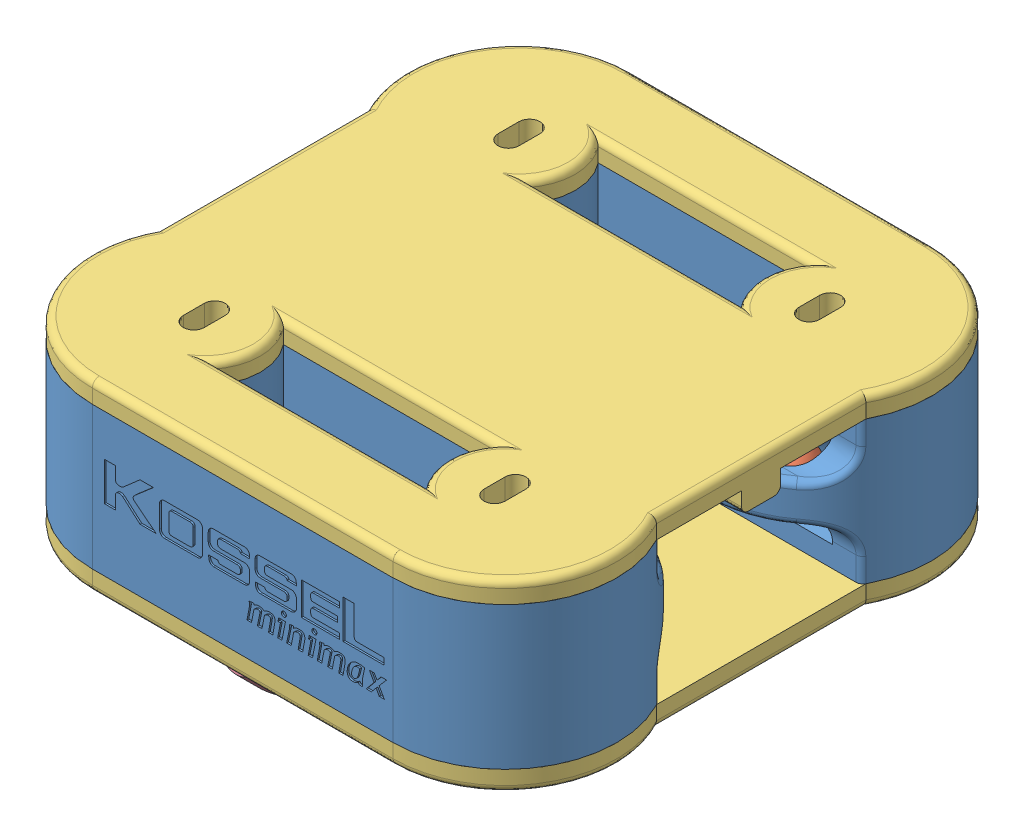
SolidWorks assembly assembled_bearing, configuration Default. Lengths in mm.
Overall size (75 49.18 77).
26 component instances, 5 part files, 17 mates.
Components (placement in the parent):
- loaded_bearing_body-1: loaded_bearing_body [Default] at origin size (75 20.4 32)
  - bearing_body-2: bearing_body [Default] at origin size (75 20.4 32)
  - delrin_ball_5-16_inch-20: delrin_ball_5-16_inch [Default] at (-21.5 0 -10.4333) size (7.94 7.94 7.94)
  - delrin_ball_5-16_inch-21: delrin_ball_5-16_inch [Default] at (-28.7803 0 -7.4723) size (7.94 7.94 7.94)
  - delrin_ball_5-16_inch-22: delrin_ball_5-16_inch [Default] at (-31.9288 0 -0.2689) size (7.94 7.94 7.94)
  - delrin_ball_5-16_inch-23: delrin_ball_5-16_inch [Default] at (-29.1561 0 7.0868) size (7.94 7.94 7.94)
  - delrin_ball_5-16_inch-24: delrin_ball_5-16_inch [Default] at (-22.036 0 10.4195) size (7.94 7.94 7.94)
  - delrin_ball_5-16_inch-25: delrin_ball_5-16_inch [Default] at (-13.9756 0 10.4333) size (7.94 7.94 7.94)
  - delrin_ball_5-16_inch-26: delrin_ball_5-16_inch [Default] at (-5.9163 0 10.4333) size (7.94 7.94 7.94)
  - delrin_ball_5-16_inch-27: delrin_ball_5-16_inch [Default] at (2.143 0 10.4333) size (7.94 7.94 7.94)
  - delrin_ball_5-16_inch-28: delrin_ball_5-16_inch [Default] at (10.2043 0 10.4333) size (7.94 7.94 7.94)
  - delrin_ball_5-16_inch-29: delrin_ball_5-16_inch [Default] at (18.2636 0 10.4333) size (7.94 7.94 7.94)
  - delrin_ball_5-16_inch-30: delrin_ball_5-16_inch [Default] at (26.1539 0 9.3383) size (7.94 7.94 7.94)
  - delrin_ball_5-16_inch-31: delrin_ball_5-16_inch [Default] at (31.3507 0 3.4405) size (7.94 7.94 7.94)
  - delrin_ball_5-16_inch-32: delrin_ball_5-16_inch [Default] at (30.9555 0 -4.4119) size (7.94 7.94 7.94)
  - delrin_ball_5-16_inch-33: delrin_ball_5-16_inch [Default] at (25.193 0 -9.7582) size (7.94 7.94 7.94)
  - delrin_ball_5-16_inch-34: delrin_ball_5-16_inch [Default] at (17.215 0 -10.4333) size (7.94 7.94 7.94)
  - delrin_ball_5-16_inch-35: delrin_ball_5-16_inch [Default] at (9.1557 0 -10.4333) size (7.94 7.94 7.94)
  - delrin_ball_5-16_inch-36: delrin_ball_5-16_inch [Default] at (1.0944 0 -10.4333) size (7.94 7.94 7.94)
  - delrin_ball_5-16_inch-37: delrin_ball_5-16_inch [Default] at (-6.9649 0 -10.4333) size (7.94 7.94 7.94)
  - delrin_ball_5-16_inch-38: delrin_ball_5-16_inch [Default] at (-15.0243 0 -10.4333) size (7.94 7.94 7.94)
- bearing_assembly_plate-1: bearing_assembly_plate [Outside] at (0 10.2 0) x (1 0 0) z (0 1 0) size (75 77 6)
- bearing_body-1: bearing_body [Default] at (0 0 45) x (-1 0 0) z (0 0 -1) size (75 20.4 32)
- bearing_assembly_plate-2: bearing_assembly_plate [Rodside-Nohole] at (0 -10.2 45) x (1 0 0) z (0 -1 0) size (75 77 12.8)
- rod_and_belt_carriage-1: rod_and_belt_carriage [Nohole] at (-19.4203 -23 22.5) x (0 0 1) z (1 0 0) size (40 12.98 32.4)
- Part2^assembled_bearing-1: Part2^assembled_bearing [Default] at (-19.4203 -23 22.5) x (0 0 -1) z (0 1 0) size (33.02 13.44 9.81) (virtual)
Mates (geometry in assembly coordinates):
- InPlace1: in place: plane of loaded_bearing_body-1/bearing_body-2 through (-22 10.2 0) normal (0 1 0); plane of bearing_assembly_plate-1 through (0 10.2 0) normal (0 1 0); moOrthogonalPlaneRef_w of loaded_bearing_body-1/bearing_body-2 through (-22 10.2 0) normal (0 1 0); plane of bearing_assembly_plate-1 through (0 10.2 0) normal (0 0 -1); plane of loaded_bearing_body-1/bearing_body-2 through (-22 10.2 0) normal (0 1 0); line of bearing_assembly_plate-1 through (-55 0 10.2) axis (0 1 0); plane of loaded_bearing_body-1/bearing_body-2 through (-21.5 10.2 0) normal (0 1 0); unknown of bearing_assembly_plate-1
- Coincident1: coincident aligned: plane of loaded_bearing_body-1/bearing_body-2; plane of bearing_assembly_plate-1
- Coincident2: coincident aligned: moOrthogonalPlaneRef_w of loaded_bearing_body-1/bearing_body-2 through (0 10.2 0) normal (0 0 -1); plane of bearing_assembly_plate-1 through (0 10.2 0) normal (0 0 -1)
- Coincident3: coincident anti-aligned: moOrthogonalPlaneRef_w of loaded_bearing_body-1/bearing_body-2 through (0 10.2 0) normal (-1 0 0); plane of bearing_assembly_plate-1
- Coincident4: coincident anti-aligned: plane of bearing_assembly_plate-1 through (-21.5 10.2 0) normal (0 -1 0); plane of bearing_body-1 through (21.5 10.2 45) normal (0 1 0)
- Coincident5: coincident aligned: plane of bearing_assembly_plate-1 through (21.5 13.2 61) normal (0 0 1); plane of bearing_body-1 through (-21.5 -10.2 61) normal (0 0 1)
- Coincident6: coincident anti-aligned: line of bearing_assembly_plate-1 through (21.5 12.2 61) axis (0 -1 0); line of bearing_body-1 through (21.5 -10.2 61) axis (0 1 0)
- Coincident7: coincident anti-aligned: plane of loaded_bearing_body-1/bearing_body-2 through (-21.5 -10.2 0) normal (0 -1 0); plane of bearing_assembly_plate-2 through (-21.5 -10.2 45) normal (0 1 0)
- Coincident8: coincident aligned: plane of loaded_bearing_body-1/bearing_body-2 through (21.5 -10.2 -16) normal (0 0 -1); plane of bearing_assembly_plate-2 through (21.5 -13.2 -16) normal (0 0 -1)
- Coincident9: coincident aligned: line of loaded_bearing_body-1/bearing_body-2 through (-21.5 -10.2 -16) axis (0 1 0); line of bearing_assembly_plate-2 through (-21.5 -12.2 -16) axis (0 1 0)
- Coincident10: coincident anti-aligned: plane of bearing_assembly_plate-2 through (0 -23 45) normal (0 -1 0); plane of rod_and_belt_carriage-1 through (-19.4203 -23 22.5) normal (0 1 0)
- Coincident11: coincident aligned: plane of bearing_assembly_plate-2 through (-35.6203 -13.2 37.4755) normal (-1 0 0); plane of rod_and_belt_carriage-1 through (-35.6203 -27 36) normal (-1 0 0)
- Coincident12: coincident aligned: plane of bearing_assembly_plate-2 through (-3.2203 -23 9) normal (0 0 -1); plane of rod_and_belt_carriage-1 through (-3.2203 -27 9) normal (0 0 -1)
- InPlace2: in place: plane of rod_and_belt_carriage-1 through (-19.4203 -23 22.5) normal (0 1 0); plane of ? through (0 -23 0) normal (0 1 0); plane of rod_and_belt_carriage-1 through (-19.4203 -23 22.5) normal (0 1 0); plane of ? through (0 -23 0) normal (0 0 -1); plane of rod_and_belt_carriage-1 through (-19.4203 -23 22.5) normal (0 1 0); line of ? through (-55 0 -23) axis (0 1 0); plane of rod_and_belt_carriage-1 through (-19.4203 -23 22.5) normal (0 1 0); unknown of Part2^assembled_bearing-1
- Coincident13: coincident aligned: plane of rod_and_belt_carriage-1; plane of Part2^assembled_bearing-1
- Coincident14: coincident aligned: moOrthogonalPlaneRef_w of rod_and_belt_carriage-1 through (-19.4203 -23 22.5) normal (-1 0 0); plane of Part2^assembled_bearing-1
- Coincident15: coincident anti-aligned: moOrthogonalPlaneRef_w of rod_and_belt_carriage-1 through (-19.4203 -23 22.5) normal (0 0 1); plane of Part2^assembled_bearing-1
